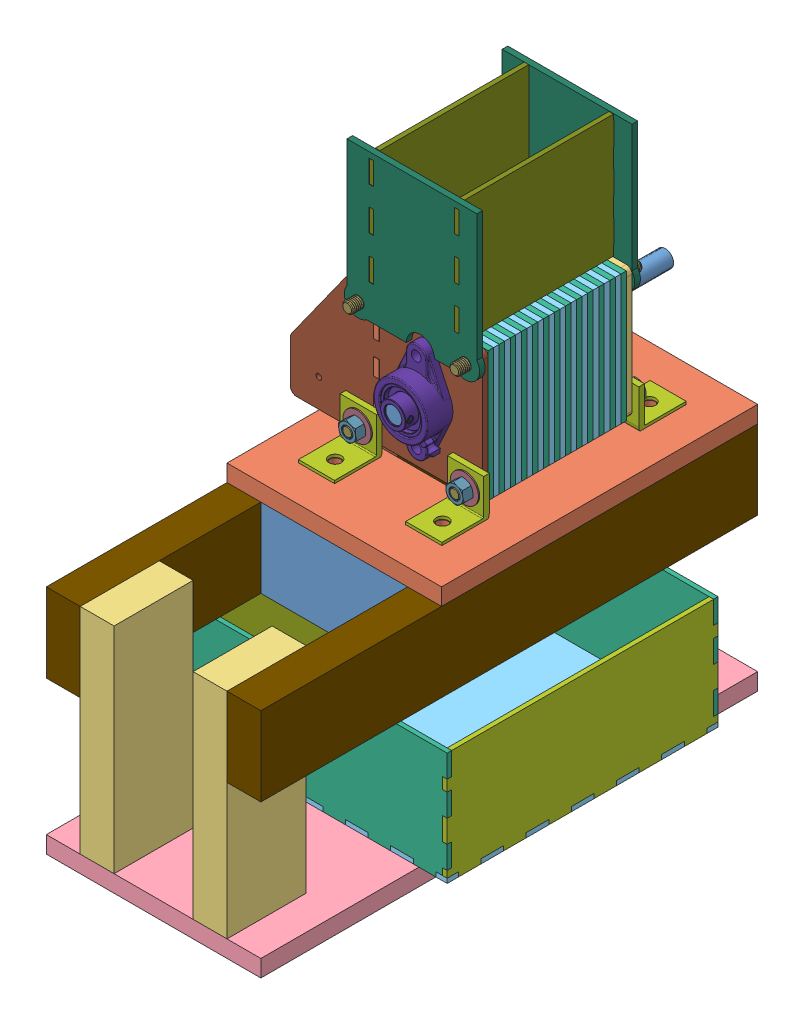
SolidWorks assembly Assembly_Single_Cutter_With_Gearbox, configuration Default. Lengths in mm.
Overall size (304.8 575.3 565.91).
95 component instances, 25 part files, 98 mates.
Components (placement in the parent):
- Axle-1: Axle [Default] at (0 0 48.387) x (0.906576 -0.422043 0) z (0 0 1) size (25.4 29.33 304.8)
- BackPlate-1: BackPlate [Default] at (-55.88 0 80.899) x (0 0 -1) z (1 0 0) size (168.66 146.05 6.35)
- Side_Plate-1: Side_Plate [Default] at origin size (146.05 146.05 6.35)
- Hex_Spacer-1: Hex_Spacer [Default] at (0 0 31.115) x (0.818788 0.574096 0) z (0 0 1) size (38.1 38.1 6.35)
- Hex_Spacer-2: Hex_Spacer [Default] at (0 0 18.669) x (0.818788 0.574096 0) z (0 0 1) size (38.1 38.1 6.35)
- Hex_Spacer-3: Hex_Spacer [Default] at (0 0 80.899) x (-0.818788 -0.574096 0) z (0 0 1) size (38.1 38.1 6.35)
- Hex_Spacer-13: Hex_Spacer [Default] at (0 0 6.223) x (0.818788 0.574096 0) z (0 0 1) size (38.1 38.1 6.35)
- Hex_Spacer-14: Hex_Spacer [Default] at (0 0 -0.127) x (0.818788 0.574096 0) z (0 0 1) size (38.1 38.1 6.35)
- Hex_Spacer-15: Hex_Spacer [Default] at (0 0 161.925) x (0.818788 0.574096 0) z (0 0 1) size (38.1 38.1 6.35)
- Spacer_1-1: Spacer_1 [Default] at (44.45 0 12.446) size (34.77 146.05 6.35)
- Spacer_2-1: Spacer_2 [Default] at (44.45 0 6.223) size (59.73 146.05 6.1)
- Spacer_2-14: Spacer_2 [Default] at (44.45 0 155.575) size (59.73 146.05 6.1)
- Spacer_2-2: Spacer_2 [Default] at (44.45 0 18.669) size (59.73 146.05 6.1)
- Spacer_2-3: Spacer_2 [Default] at (44.45 0 31.115) size (59.73 146.05 6.1)
- Spacer_2-4: Spacer_2 [Default] at (44.45 0 43.561) size (59.73 146.05 6.1)
- Spacer_2-5: Spacer_2 [Default] at (44.45 0 56.007) size (59.73 146.05 6.1)
- Spacer_2-6: Spacer_2 [Default] at (44.45 0 68.453) size (59.73 146.05 6.1)
- Spacer_2-7: Spacer_2 [Default] at (44.45 0 80.899) size (59.73 146.05 6.1)
- Spacer_2-8: Spacer_2 [Default] at (44.45 0 93.345) size (59.73 146.05 6.1)
- Spacer_2-9: Spacer_2 [Default] at (44.45 0 105.791) size (59.73 146.05 6.1)
- Spacer_2-10: Spacer_2 [Default] at (44.45 0 118.237) size (59.73 146.05 6.1)
- Spacer_2-11: Spacer_2 [Default] at (44.45 0 130.683) size (59.73 146.05 6.1)
- Spacer_2-12: Spacer_2 [Default] at (44.45 0 143.129) size (59.73 146.05 6.1)
- Spacer_1-3: Spacer_1 [Default] at (44.45 0 24.892) size (34.77 146.05 6.35)
- Spacer_1-4: Spacer_1 [Default] at (44.45 0 37.338) size (34.77 146.05 6.35)
- Spacer_1-5: Spacer_1 [Default] at (44.45 0 49.784) size (34.77 146.05 6.35)
- Spacer_1-6: Spacer_1 [Default] at (44.45 0 62.23) size (34.77 146.05 6.35)
- Spacer_1-7: Spacer_1 [Default] at (44.45 0 74.676) size (34.77 146.05 6.35)
- Spacer_1-8: Spacer_1 [Default] at (44.45 0 87.122) size (34.77 146.05 6.35)
- Spacer_1-9: Spacer_1 [Default] at (44.45 0 99.568) size (34.77 146.05 6.35)
- Spacer_1-10: Spacer_1 [Default] at (44.45 0 112.014) size (34.77 146.05 6.35)
- Spacer_1-11: Spacer_1 [Default] at (44.45 0 124.46) size (34.77 146.05 6.35)
- Spacer_1-12: Spacer_1 [Default] at (44.45 0 136.906) size (34.77 146.05 6.35)
- Spacer_1-13: Spacer_1 [Default] at (44.45 0 149.352) size (34.77 146.05 6.35)
- Base_Clamp-1: Base_Clamp [Default] at (-69.85 -80.01 171.323) x (0 1 0) z (1 0 0) size (46.99 53.34 40.64)
- Base_Clamp-2: Base_Clamp [Default] at (50.8 -80.01 171.323) x (0 1 0) z (1 0 0) size (46.99 53.34 40.64)
- Base_Clamp-3: Base_Clamp [Default] at (50.8 -80.01 -9.525) x (0 1 0) z (-1 0 0) size (46.99 53.34 40.64)
- Base_Clamp-4: Base_Clamp [Default] at (-69.85 -80.01 -9.525) x (0 1 0) z (-1 0 0) size (46.99 53.34 40.64)
- 2Tooth_Cutter_V1_2-1: 2Tooth_Cutter_V1_2 [Default] at (0 0 24.892) x (0.258206 0.96609 0) z (0 0 1) size (75.28 102.63 6.1)
- 2Tooth_Cutter_V1-1: 2Tooth_Cutter_V1 [Default] at (0 0 12.446) x (-0.087788 0.996139 0) z (0 0 1) size (75.28 104.14 6.1)
- 2Tooth_Cutter_V1_3-1: 2Tooth_Cutter_V1_3 [Default] at (0 0 37.338) x (0.573056 0.819516 0) z (0 0 1) size (75.28 102.63 6.1)
- Hex_Spacer-20: Hex_Spacer [Default] at (0 0 68.453) x (0.906576 -0.422043 0) z (0 0 1) size (38.1 38.1 6.35)
- Hex_Spacer-21: Hex_Spacer [Default] at (0 0 56.007) x (0.906576 -0.422043 0) z (0 0 1) size (38.1 38.1 6.35)
- Hex_Spacer-22: Hex_Spacer [Default] at (0 0 43.561) x (0.906576 -0.422043 0) z (0 0 1) size (38.1 38.1 6.35)
- 2Tooth_Cutter_V1_3-3: 2Tooth_Cutter_V1_3 [Default] at (0 0 74.676) x (0.99625 -0.086523 0) z (0 0 1) size (75.28 102.63 6.1)
- 2Tooth_Cutter_V1_2-3: 2Tooth_Cutter_V1_2 [Default] at (0 0 62.23) x (0.965761 0.259432 0) z (0 0 1) size (75.28 102.63 6.1)
- 2Tooth_Cutter_V1-3: 2Tooth_Cutter_V1 [Default] at (0 0 49.784) x (0.818788 0.574096 0) z (0 0 1) size (75.28 104.14 6.1)
- 2Tooth_Cutter_V1-4: 2Tooth_Cutter_V1 [Default] at (0 0 87.122) x (0.906576 -0.422043 0) z (0 0 1) size (75.28 104.14 6.1)
- 2Tooth_Cutter_V1-5: 2Tooth_Cutter_V1 [Default] at (0 0 124.46) x (0.087788 -0.996139 0) z (0 0 1) size (75.28 104.14 6.1)
- 2Tooth_Cutter_V1_2-4: 2Tooth_Cutter_V1_2 [Default] at (0 0 99.568) x (0.707556 -0.706658 0) z (0 0 1) size (75.28 102.63 6.1)
- 2Tooth_Cutter_V1_2-5: 2Tooth_Cutter_V1_2 [Default] at (0 0 136.906) x (-0.258206 -0.96609 0) z (0 0 1) size (75.28 102.63 6.1)
- 2Tooth_Cutter_V1_3-4: 2Tooth_Cutter_V1_3 [Default] at (0 0 112.014) x (0.423194 -0.906039 0) z (0 0 1) size (75.28 102.63 6.1)
- 2Tooth_Cutter_V1_3-5: 2Tooth_Cutter_V1_3 [Default] at (0 0 149.352) x (-0.573056 -0.819516 0) z (0 0 1) size (75.28 102.63 6.1)
- Hex_Spacer-23: Hex_Spacer [Default] at (0 0 80.899) x (0.087788 -0.996139 0) z (0 0 1) size (38.1 38.1 6.35)
- Hex_Spacer-24: Hex_Spacer [Default] at (0 0 118.237) x (-0.818788 -0.574096 0) z (0 0 1) size (38.1 38.1 6.35)
- Hex_Spacer-25: Hex_Spacer [Default] at (0 0 93.345) x (0.087788 -0.996139 0) z (0 0 1) size (38.1 38.1 6.35)
- Hex_Spacer-26: Hex_Spacer [Default] at (0 0 130.683) x (-0.818788 -0.574096 0) z (0 0 1) size (38.1 38.1 6.35)
- Hex_Spacer-27: Hex_Spacer [Default] at (0 0 105.791) x (0.087788 -0.996139 0) z (0 0 1) size (38.1 38.1 6.35)
- Hex_Spacer-28: Hex_Spacer [Default] at (0 0 143.129) x (-0.818788 -0.574096 0) z (0 0 1) size (38.1 38.1 6.35)
- Hex_Spacer-29: Hex_Spacer [Default] at (0 0 155.575) x (0.818788 0.574096 0) z (0 0 1) size (38.1 38.1 6.35)
- Side_Plate_With_Gear_Reduction-1: Side_Plate_With_Gear_Reduction [Default] at (0 0 161.798) size (215.9 146.05 6.35)
- 8in_Threaded_Rod-1: 8in_Threaded_Rod [3313N13] at (50.8 60.325 80.899) x (0 0 1) z (-1 0 0) size (209.49 12.88 14.68)
- 8in_Threaded_Rod-2: 8in_Threaded_Rod [3313N13] at (50.8 -60.325 80.899) x (0 0 1) z (-1 0 0) size (209.49 12.88 14.68)
- 8in_Threaded_Rod-3: 8in_Threaded_Rod [3313N13] at (-69.85 -60.325 80.899) x (0 0 1) z (-1 0 0) size (209.49 12.88 14.68)
- 8in_Threaded_Rod-4: 8in_Threaded_Rod [3313N13] at (-69.85 60.325 80.899) x (0 0 1) z (-1 0 0) size (209.49 12.88 14.68)
- 90107A033_TYPE 316 STAINLESS STEEL FLAT WASHER-2: 90107A033_TYPE 316 STAINLESS STEEL FLAT WASHER [90107A033] at (-69.85 -60.325 172.72) x (1 0 0) z (0 1 0) size (31.75 1.4 31.75)
- 90107A033_TYPE 316 STAINLESS STEEL FLAT WASHER-3: 90107A033_TYPE 316 STAINLESS STEEL FLAT WASHER [90107A033] at (50.8 -60.325 172.72) x (1 0 0) z (0 1 0) size (31.75 1.4 31.75)
- 95462A033_GRADE 5 STEEL HEX NUT-3: 95462A033_GRADE 5 STEEL HEX NUT [95462A033] at (-69.85 -60.325 178.2763) x (0.986139 0.165922 0) z (0 0 1) size (19.05 22 14.07)
- 95462A033_GRADE 5 STEEL HEX NUT-4: 95462A033_GRADE 5 STEEL HEX NUT [95462A033] at (50.8 -60.325 178.2763) x (0.983888 0.178788 0) z (0 0 1) size (19.05 22 14.07)
- 95462A033_GRADE 5 STEEL HEX NUT-5: 95462A033_GRADE 5 STEEL HEX NUT [95462A033] at (50.8 -60.325 -16.5447) x (0.983888 0.178788 0) z (0 0 1) size (19.05 22 14.07)
- 95462A033_GRADE 5 STEEL HEX NUT-6: 95462A033_GRADE 5 STEEL HEX NUT [95462A033] at (-69.85 -60.325 -16.5447) x (0.986139 0.165922 0) z (0 0 1) size (19.05 22 14.07)
- 90107A033_TYPE 316 STAINLESS STEEL FLAT WASHER-10: 90107A033_TYPE 316 STAINLESS STEEL FLAT WASHER [90107A033] at (50.8 -60.325 -10.922) x (1 0 0) z (0 -1 0) size (31.75 1.4 31.75)
- 90107A033_TYPE 316 STAINLESS STEEL FLAT WASHER-11: 90107A033_TYPE 316 STAINLESS STEEL FLAT WASHER [90107A033] at (-69.85 -60.325 -10.922) x (1 0 0) z (0 -1 0) size (31.75 1.4 31.75)
- Hopper_Front_Plate-1: Hopper_Front_Plate [Default] at (-9.525 60.325 -6.35) size (152.4 168.28 6.35)
- Hopper_Front_Plate-2: Hopper_Front_Plate [Default] at (-9.525 60.325 168.148) size (152.4 168.28 6.35)
- Hopper_Side_Plate-1: Hopper_Side_Plate [Default] at (-52.578 143.51 80.645) x (0 0 1) z (-1 0 0) size (180.34 138.43 5.08)
- Hopper_Side_Plate-2: Hopper_Side_Plate [Default] at (43.18 143.51 81.153) x (0 0 1) z (-1 0 0) size (180.34 138.43 5.08)
- 5968K730_TWO-BOLT FLANGE-MOUNT SELF-ALIGNING BALL BRNG-1: 5968K730_TWO-BOLT FLANGE-MOUNT SELF-ALIGNING BALL BRNG [5968K73] at (0 0 183.6261) x (0 -1 0) z (0 0 1) size (112.71 64.05 37.31)
- Shredder_Chassis_Subassembly-1: Shredder_Chassis_Subassembly [Default] at (-111.125 -146.6799 182.499) size (304.8 279.4 558.8)
  - Side_Wall-1: Side_Wall [Default] at origin size (38.1 88.9 558.8)
  - 2x4x6.5-1: 2x4x6.5 [Default] at (101.6 0 -260.35) x (0 0 1) z (-1 0 0) size (38.1 88.9 165.1)
  - Side_Wall-2: Side_Wall [Default] at (203.2 0 0) size (38.1 88.9 558.8)
  - 2x4x6.5-2: 2x4x6.5 [Default] at (101.6 0 57.15) x (0 0 1) z (-1 0 0) size (38.1 88.9 165.1)
  - Top_Plate-1: Top_Plate [Default] at (101.6 53.975 -101.6) size (241.3 19.05 355.6)
  - 2x4x9.5-1: 2x4x9.5 [Default] at (38.1 -76.2 234.95) size (38.1 241.3 88.9)
  - 2x4x9.5-2: 2x4x9.5 [Default] at (165.1 -76.2 234.95) size (38.1 241.3 88.9)
  - 2x4x9.5-3: 2x4x9.5 [Default] at (101.6 -76.2 -222.25) x (0 0 -1) z (1 0 0) size (38.1 241.3 88.9)
  - Bottom_Plate-1: Bottom_Plate [Default] at (101.6 -206.375 0) size (241.3 19.05 558.8)
  - Box_Subassembly-1: Box_Subassembly [Default] at (101.6 -194.31 -50.8) size (304.8 127 304.8)
    - Box_Bottom-1: Box_Bottom [Default] at origin size (304.8 5.08 304.8)
    - Box_Side1-1: Box_Side1 [Default] at (0 124.46 149.86) size (304.8 127 5.08)
    - Box_Side1-2: Box_Side1 [Default] at (0 124.46 -149.86) size (304.8 127 5.08)
    - Box_Side2-1: Box_Side2 [Default] at (149.86 124.46 0) x (0 0 -1) z (1 0 0) size (304.8 127 5.08)
    - Box_Side2-2: Box_Side2 [Default] at (-149.86 124.46 0) x (0 0 -1) z (1 0 0) size (304.8 127 5.08)
- 5968K730_TWO-BOLT FLANGE-MOUNT SELF-ALIGNING BALL BRNG-2: 5968K730_TWO-BOLT FLANGE-MOUNT SELF-ALIGNING BALL BRNG [5968K73] at (0 0 -21.8281) x (0 -1 0) z (0 0 -1) size (112.71 64.05 37.31)
Mates (geometry in assembly coordinates):
- Coincident15: coincident aligned: plane of BackPlate-1 through (-55.88 0 80.899) normal (0 1 0); plane of assembly through (0 0 0) normal (0 1 0)
- Coincident19: coincident aligned: plane of Side_Plate-1 through (0 0 0) normal (0 0 1); plane of assembly through (0 0 0) normal (0 0 1)
- Coincident20: coincident aligned: plane of Side_Plate-1 through (0 0 0) normal (1 0 0); plane of assembly through (0 0 0) normal (1 0 0)
- Coincident21: coincident aligned: plane of Side_Plate-1 through (0 0 0) normal (0 1 0); plane of assembly through (0 0 0) normal (0 1 0)
- Coincident22: coincident aligned: plane of BackPlate-1 through (-55.88 0 80.899) normal (1 0 0); plane of assembly through (-55.88 0 0) normal (1 0 0)
- Coincident23: coincident anti-aligned: plane of BackPlate-1 through (-52.705 73.025 3.175) normal (0 0 -1); plane of Side_Plate-1 through (0 0 3.175) normal (0 0 1)
- Concentric9: concentric aligned: cylinder of Axle-1 through (0 0 200.787) axis (0 0 -1) radius 9.525; cylinder of Side_Plate-1 through (0 0 3.175) axis (0 0 -1) radius 19.05
- Coincident25: coincident aligned: line of Axle-1 through (-14.6081 -1.2874 165.227) axis (0 0 -1); line of Hex_Spacer-1 through (-14.6081 -1.2874 34.29) axis (0 0 -1)
- Coincident26: coincident aligned: line of Axle-1 through (14.6081 1.2874 165.227) axis (0 0 -1); line of Hex_Spacer-1 through (14.6081 1.2874 34.29) axis (0 0 -1)
- Concentric14: concentric aligned: cylinder of Side_Plate-1 through (50.8 -60.325 3.175) axis (0 0 -1) radius 6.35; cylinder of Spacer_1-1 through (50.8 -60.325 15.621) axis (0 0 -1) radius 6.3627
- Concentric15: concentric aligned: cylinder of Side_Plate-1 through (50.8 60.325 3.175) axis (0 0 -1) radius 6.35; cylinder of Spacer_1-1 through (50.8 60.325 15.621) axis (0 0 -1) radius 6.3627
- Concentric16: concentric aligned: cylinder of Side_Plate-1 through (50.8 60.325 3.175) axis (0 0 -1) radius 6.35; cylinder of Spacer_2-1 through (50.8 60.325 9.271) axis (0 0 -1) radius 6.3627
- Concentric17: concentric aligned: cylinder of Side_Plate-1 through (50.8 -60.325 3.175) axis (0 0 -1) radius 6.35; cylinder of Spacer_2-1 through (50.8 -60.325 9.271) axis (0 0 -1) radius 6.3627
- Coincident38: coincident anti-aligned: plane of Side_Plate-1 through (0 0 3.175) normal (0 0 1); plane of Spacer_2-1 through (44.45 0 3.175) normal (0 0 -1)
- Coincident39: coincident anti-aligned: plane of Spacer_1-1 through (44.45 0 9.271) normal (0 0 -1); plane of Spacer_2-1 through (44.45 0 9.271) normal (0 0 1)
- Coincident40: coincident anti-aligned: plane of Spacer_1-13 through (44.45 0 152.527) normal (0 0 1); plane of Spacer_2-14 through (44.45 0 152.527) normal (0 0 -1)
- Concentric19: concentric aligned: cylinder of Side_Plate-1 through (50.8 -60.325 3.175) axis (0 0 -1) radius 6.35; cylinder of Spacer_2-14 through (50.8 -60.325 158.623) axis (0 0 -1) radius 6.3627
- Concentric20: concentric aligned: cylinder of Side_Plate-1 through (50.8 60.325 3.175) axis (0 0 -1) radius 6.35; cylinder of Spacer_2-14 through (50.8 60.325 158.623) axis (0 0 -1) radius 6.3627
- Coincident44: coincident aligned: line of Axle-1 through (6.1891 13.2947 165.227) axis (0 0 -1); line of Hex_Spacer-2 through (6.1891 13.2947 21.844) axis (0 0 -1)
- Coincident45: coincident aligned: line of Axle-1 through (-6.1891 -13.2947 165.227) axis (0 0 -1); line of Hex_Spacer-2 through (-6.1891 -13.2947 21.844) axis (0 0 -1)
- Coincident54: coincident aligned: line of Axle-1 through (8.419 -12.0073 165.227) axis (0 0 -1); line of Hex_Spacer-3 through (8.419 -12.0073 84.074) axis (0 0 -1)
- Coincident55: coincident aligned: line of Axle-1 through (6.1891 13.2947 165.227) axis (0 0 -1); line of Hex_Spacer-3 through (6.1891 13.2947 84.074) axis (0 0 -1)
- Coincident57: coincident aligned: plane of Axle-1 through (0 0 -3.175) normal (0 0 -1); plane of Side_Plate-1 through (0 0 -3.175) normal (0 0 -1)
- Coincident58: coincident aligned: line of Axle-1 through (6.1891 13.2947 165.227) axis (0 0 -1); line of Hex_Spacer-13 through (6.1891 13.2947 9.398) axis (0 0 -1)
- Coincident59: coincident aligned: line of Axle-1 through (-6.1891 -13.2947 165.227) axis (0 0 -1); line of Hex_Spacer-13 through (-6.1891 -13.2947 9.398) axis (0 0 -1)
- Coincident61: coincident aligned: line of Axle-1 through (6.1891 13.2947 165.227) axis (0 0 -1); line of Hex_Spacer-14 through (6.1891 13.2947 3.048) axis (0 0 -1)
- Coincident62: coincident aligned: line of Axle-1 through (-6.1891 -13.2947 165.227) axis (0 0 -1); line of Hex_Spacer-14 through (-6.1891 -13.2947 3.048) axis (0 0 -1)
- Coincident63: coincident anti-aligned: plane of Hex_Spacer-13 through (0 0 3.048) normal (0 0 -1); plane of Hex_Spacer-14 through (0 0 3.048) normal (0 0 1)
- Coincident64: coincident aligned: line of Axle-1 through (6.1891 13.2947 165.227) axis (0 0 -1); line of Hex_Spacer-15 through (6.1891 13.2947 165.1) axis (0 0 -1)
- Coincident65: coincident aligned: line of Axle-1 through (-6.1891 -13.2947 165.227) axis (0 0 -1); line of Hex_Spacer-15 through (-6.1891 -13.2947 165.1) axis (0 0 -1)
- Coincident69: coincident aligned: plane of Spacer_1-1 through (44.45 0 12.446) normal (0 0 1); plane of 2Tooth_Cutter_V1-1 through (0 0 12.446) normal (0 0 1)
- Parallel1: parallel aligned: line of Axle-1 through (8.419 -12.0073 165.227) axis (0 0 -1); line of 2Tooth_Cutter_V1_2-1 through (-8.419 12.0073 27.94) axis (0 0 -1)
- Coincident80: coincident aligned: line of Axle-1 through (-8.419 12.0073 165.227) axis (0 0 -1); line of 2Tooth_Cutter_V1-1 through (-8.419 12.0073 15.494) axis (0 0 -1)
- Coincident81: coincident aligned: line of Axle-1 through (-6.1891 -13.2947 165.227) axis (0 0 -1); line of 2Tooth_Cutter_V1-1 through (-6.1891 -13.2947 15.494) axis (0 0 -1)
- Coincident82: coincident aligned: line of Axle-1 through (-8.419 12.0073 165.227) axis (0 0 -1); line of 2Tooth_Cutter_V1_2-1 through (-8.419 12.0073 27.94) axis (0 0 -1)
- Coincident83: coincident aligned: line of Axle-1 through (-6.1891 -13.2947 165.227) axis (0 0 -1); line of 2Tooth_Cutter_V1_2-1 through (-6.1891 -13.2947 27.94) axis (0 0 -1)
- Coincident84: coincident anti-aligned: plane of Hex_Spacer-2 through (0 0 21.844) normal (0 0 1); plane of 2Tooth_Cutter_V1_2-1 through (0 0 21.844) normal (0 0 -1)
- Coincident85: coincident anti-aligned: plane of Hex_Spacer-2 through (0 0 15.494) normal (0 0 -1); plane of 2Tooth_Cutter_V1-1 through (0 0 15.494) normal (0 0 1)
- Coincident87: coincident aligned: line of Axle-1 through (-8.419 12.0073 165.227) axis (0 0 -1); line of 2Tooth_Cutter_V1_3-1 through (-8.419 12.0073 40.386) axis (0 0 -1)
- Coincident88: coincident aligned: line of Axle-1 through (-6.1891 -13.2947 165.227) axis (0 0 -1); line of 2Tooth_Cutter_V1_3-1 through (-6.1891 -13.2947 40.386) axis (0 0 -1)
- Coincident89: coincident anti-aligned: plane of Hex_Spacer-1 through (0 0 27.94) normal (0 0 -1); plane of 2Tooth_Cutter_V1_2-1 through (0 0 27.94) normal (0 0 1)
- Coincident90: coincident anti-aligned: plane of Hex_Spacer-1 through (0 0 34.29) normal (0 0 1); plane of 2Tooth_Cutter_V1_3-1 through (0 0 34.29) normal (0 0 -1)
- Coincident91: coincident anti-aligned: plane of Hex_Spacer-3 through (0 0 77.724) normal (0 0 -1); plane of 2Tooth_Cutter_V1_3-3 through (0 0 77.724) normal (0 0 1)
- Coincident92: coincident aligned: line of Axle-1 through (8.419 -12.0073 165.227) axis (0 0 -1); line of Hex_Spacer-29 through (8.419 -12.0073 158.75) axis (0 0 -1)
- Coincident93: coincident aligned: line of Axle-1 through (14.6081 1.2874 165.227) axis (0 0 -1); line of Hex_Spacer-29 through (14.6081 1.2874 158.75) axis (0 0 -1)
- Coincident94: coincident anti-aligned: plane of 2Tooth_Cutter_V1_3-5 through (0 0 152.4) normal (0 0 1); plane of Hex_Spacer-29 through (0 0 152.4) normal (0 0 -1)
- Coincident95: coincident anti-aligned: plane of Hex_Spacer-15 through (0 0 158.75) normal (0 0 -1); plane of Hex_Spacer-29 through (0 0 158.75) normal (0 0 1)
- Concentric21: concentric aligned: cylinder of Spacer_2-14 through (50.8 -60.325 158.623) axis (0 0 -1) radius 6.3627; cylinder of Side_Plate_With_Gear_Reduction-1 through (50.8 -60.325 164.973) axis (0 0 -1) radius 6.35
- Coincident96: coincident anti-aligned: plane of Spacer_2-14 through (44.45 0 158.623) normal (0 0 1); plane of Side_Plate_With_Gear_Reduction-1 through (0 0 158.623) normal (0 0 -1)
- Concentric22: concentric aligned: cylinder of Spacer_2-14 through (50.8 60.325 158.623) axis (0 0 -1) radius 6.3627; cylinder of Side_Plate_With_Gear_Reduction-1 through (50.8 60.325 164.973) axis (0 0 -1) radius 6.35
- Concentric23: concentric anti-aligned: cylinder of Side_Plate_With_Gear_Reduction-1 through (-69.85 -60.325 164.973) axis (0 0 -1) radius 6.35; cylinder of Base_Clamp-1 through (-69.85 -60.325 164.972) axis (0 0 1) radius 6.985
- Coincident97: coincident anti-aligned: plane of Side_Plate_With_Gear_Reduction-1 through (0 0 164.973) normal (0 0 1); plane of Base_Clamp-1 through (-49.53 -78.74 164.973) normal (0 0 -1)
- Parallel2: parallel aligned: plane of BackPlate-1 through (-52.705 -73.025 3.175) normal (0 -1 0); plane of Base_Clamp-1 through (-49.53 -86.36 218.313) normal (0 -1 0)
- Concentric24: concentric anti-aligned: cylinder of Side_Plate_With_Gear_Reduction-1 through (50.8 -60.325 164.973) axis (0 0 -1) radius 6.35; cylinder of Base_Clamp-2 through (50.8 -60.325 164.972) axis (0 0 1) radius 6.985
- Coincident99: coincident anti-aligned: plane of Side_Plate_With_Gear_Reduction-1 through (0 0 164.973) normal (0 0 1); plane of Base_Clamp-2 through (71.12 -78.74 164.973) normal (0 0 -1)
- Coincident100: coincident aligned: plane of Base_Clamp-1 through (-49.53 -86.36 218.313) normal (0 -1 0); plane of Base_Clamp-2 through (71.12 -86.36 218.313) normal (0 -1 0)
- Coincident101: coincident anti-aligned: plane of Side_Plate-1 through (0 0 -3.175) normal (0 0 -1); plane of Base_Clamp-3 through (30.48 -78.74 -3.175) normal (0 0 1)
- Concentric25: concentric aligned: cylinder of Side_Plate-1 through (50.8 -60.325 3.175) axis (0 0 -1) radius 6.35; cylinder of Base_Clamp-3 through (50.8 -60.325 -3.174) axis (0 0 -1) radius 6.985
- Coincident102: coincident aligned: plane of Base_Clamp-2 through (71.12 -86.36 218.313) normal (0 -1 0); plane of Base_Clamp-3 through (30.48 -86.36 -56.515) normal (0 -1 0)
- Coincident103: coincident anti-aligned: plane of Side_Plate-1 through (0 0 -3.175) normal (0 0 -1); plane of Base_Clamp-4 through (-90.17 -78.74 -3.175) normal (0 0 1)
- Concentric26: concentric aligned: cylinder of Side_Plate-1 through (-69.85 -60.325 3.175) axis (0 0 -1) radius 6.35; cylinder of Base_Clamp-4 through (-69.85 -60.325 -3.174) axis (0 0 -1) radius 6.985
- Coincident104: coincident aligned: plane of Base_Clamp-3 through (30.48 -86.36 -56.515) normal (0 -1 0); plane of Base_Clamp-4 through (-90.17 -86.36 -56.515) normal (0 -1 0)
- Concentric27: concentric anti-aligned: cylinder of Side_Plate_With_Gear_Reduction-1 through (50.8 60.325 164.973) axis (0 0 -1) radius 6.35; line of 8in_Threaded_Rod-1 through (50.8 60.325 -20.6326) axis (0 0 1)
- Coincident105: coincident aligned: plane of 8in_Threaded_Rod-1 through (50.8 60.325 80.899) normal (0 0 1); plane of assembly through (0 0 80.899) normal (0 0 1)
- Concentric28: concentric aligned: cylinder of Base_Clamp-1 through (-69.85 -60.325 164.972) axis (0 0 1) radius 6.985; line of 8in_Threaded_Rod-3 through (-69.85 -60.325 -20.6326) axis (0 0 1)
- Coincident106: coincident aligned: plane of 8in_Threaded_Rod-3 through (-69.85 -60.325 80.899) normal (0 0 1); plane of assembly through (0 0 80.899) normal (0 0 1)
- Concentric30: concentric aligned: cylinder of Base_Clamp-2 through (50.8 -60.325 164.972) axis (0 0 1) radius 6.985; line of 8in_Threaded_Rod-2 through (50.8 -60.325 -20.6326) axis (0 0 1)
- Coincident107: coincident aligned: plane of 8in_Threaded_Rod-2 through (50.8 -60.325 80.899) normal (0 0 1); plane of assembly through (0 0 80.899) normal (0 0 1)
- Concentric31: concentric anti-aligned: cylinder of Side_Plate_With_Gear_Reduction-1 through (-69.85 60.325 164.973) axis (0 0 -1) radius 6.35; line of 8in_Threaded_Rod-4 through (-69.85 60.325 -20.6326) axis (0 0 1)
- Coincident108: coincident aligned: plane of 8in_Threaded_Rod-4 through (-69.85 60.325 80.899) normal (0 0 1); plane of assembly through (0 0 80.899) normal (0 0 1)
- Coincident110: coincident anti-aligned: plane of Base_Clamp-1 through (-49.53 -39.37 171.323) normal (0 0 1); plane of 90107A033_TYPE 316 STAINLESS STEEL FLAT WASHER-2 through (-69.85 -60.325 171.323) normal (0 0 -1)
- Concentric33: concentric anti-aligned: line of 8in_Threaded_Rod-3 through (-69.85 -60.325 -20.6326) axis (0 0 1); cylinder of 90107A033_TYPE 316 STAINLESS STEEL FLAT WASHER-2 through (-69.85 -60.325 172.72) axis (0 0 -1) radius 6.7437
- Concentric34: concentric anti-aligned: line of 8in_Threaded_Rod-2 through (50.8 -60.325 -20.6326) axis (0 0 1); cylinder of 90107A033_TYPE 316 STAINLESS STEEL FLAT WASHER-3 through (50.8 -60.325 172.72) axis (0 0 -1) radius 6.7437
- Coincident111: coincident anti-aligned: plane of Base_Clamp-2 through (71.12 -39.37 171.323) normal (0 0 1); plane of 90107A033_TYPE 316 STAINLESS STEEL FLAT WASHER-3 through (50.8 -60.325 171.323) normal (0 0 -1)
- Coincident117: coincident anti-aligned: line of 8in_Threaded_Rod-3 through (-69.85 -60.325 -20.6326) axis (0 0 1); line of 95462A033_GRADE 5 STEEL HEX NUT-3 through (-69.85 -60.325 183.8325) axis (0 0 -1)
- Coincident118: coincident anti-aligned: plane of 90107A033_TYPE 316 STAINLESS STEEL FLAT WASHER-2 through (-69.85 -60.325 172.72) normal (0 0 1); plane of 95462A033_GRADE 5 STEEL HEX NUT-3 through (-80.1554 -56.4824 172.72) normal (0 0 -1)
- Coincident119: coincident anti-aligned: line of 8in_Threaded_Rod-2 through (50.8 -60.325 -20.6326) axis (0 0 1); line of 95462A033_GRADE 5 STEEL HEX NUT-4 through (50.8 -60.325 186.9915) axis (0 0 -1)
- Coincident120: coincident anti-aligned: plane of 90107A033_TYPE 316 STAINLESS STEEL FLAT WASHER-3 through (50.8 -60.325 172.72) normal (0 0 1); plane of 95462A033_GRADE 5 STEEL HEX NUT-4 through (40.4453 -56.6173 172.72) normal (0 0 -1)
- Coincident124: coincident anti-aligned: plane of Side_Plate-1 through (0 0 -3.175) normal (0 0 -1); plane of Hopper_Front_Plate-1 through (-9.525 60.325 -3.175) normal (0 0 1)
- Concentric39: concentric anti-aligned: cylinder of 8in_Threaded_Rod-4 through (-69.85 60.325 -22.098) axis (0 0 1) radius 6.35; cylinder of Hopper_Front_Plate-1 through (-69.85 60.325 -3.175) axis (0 0 -1) radius 6.35
- Concentric40: concentric anti-aligned: cylinder of 8in_Threaded_Rod-1 through (50.8 60.325 -22.098) axis (0 0 1) radius 6.35; cylinder of Hopper_Front_Plate-1 through (50.8 60.325 -3.175) axis (0 0 -1) radius 6.35
- Concentric41: concentric anti-aligned: cylinder of 8in_Threaded_Rod-4 through (-69.85 60.325 -22.098) axis (0 0 1) radius 6.35; cylinder of Hopper_Front_Plate-2 through (-69.85 60.325 171.323) axis (0 0 -1) radius 6.35
- Coincident125: coincident anti-aligned: plane of Side_Plate_With_Gear_Reduction-1 through (0 0 164.973) normal (0 0 1); plane of Hopper_Front_Plate-2 through (-9.525 60.325 164.973) normal (0 0 -1)
- Concentric42: concentric anti-aligned: cylinder of 8in_Threaded_Rod-1 through (50.8 60.325 -22.098) axis (0 0 1) radius 6.35; cylinder of Hopper_Front_Plate-2 through (50.8 60.325 171.323) axis (0 0 -1) radius 6.35
- Coincident126: coincident anti-aligned: plane of Hopper_Front_Plate-1 through (-9.525 60.325 -3.175) normal (0 0 1); plane of Hopper_Side_Plate-1 through (-57.658 158.75 -3.175) normal (0 0 -1)
- Coincident127: coincident anti-aligned: plane of Hopper_Front_Plate-1 through (-57.658 180.975 -9.525) normal (0 1 0); plane of Hopper_Side_Plate-1 through (-57.658 180.975 -3.175) normal (0 -1 0)
- Coincident128: coincident anti-aligned: plane of Hopper_Front_Plate-1 through (-57.658 206.375 -9.525) normal (1 0 0); plane of Hopper_Side_Plate-1 through (-57.658 143.51 80.645) normal (-1 0 0)
- Coincident129: coincident anti-aligned: plane of Hopper_Front_Plate-2 through (38.1 206.375 164.973) normal (1 0 0); plane of Hopper_Side_Plate-2 through (38.1 143.51 81.153) normal (-1 0 0)
- Coincident130: coincident anti-aligned: plane of Hopper_Front_Plate-2 through (-9.525 60.325 164.973) normal (0 0 -1); plane of Hopper_Side_Plate-2 through (38.1 206.375 164.973) normal (0 0 1)
- Coincident131: coincident anti-aligned: plane of Hopper_Front_Plate-2 through (38.1 180.975 164.973) normal (0 1 0); plane of Hopper_Side_Plate-2 through (38.1 180.975 164.973) normal (0 -1 0)
- Coincident132: coincident anti-aligned: plane of Side_Plate_With_Gear_Reduction-1 through (0 0 164.973) normal (0 0 1); plane of 5968K730_TWO-BOLT FLANGE-MOUNT SELF-ALIGNING BALL BRNG-1 through (0 0 164.973) normal (0 0 -1)
- Concentric50: concentric aligned: cylinder of Axle-1 through (0 0 200.787) axis (0 0 -1) radius 9.525; cylinder of 5968K730_TWO-BOLT FLANGE-MOUNT SELF-ALIGNING BALL BRNG-1 through (0 0 202.2792) axis (0 0 -1) radius 9.525
- Coincident133: coincident aligned: plane of 5968K730_TWO-BOLT FLANGE-MOUNT SELF-ALIGNING BALL BRNG-1 through (0 0 183.6261) normal (1 0 0)
- Concentric51: concentric aligned: cylinder of Base_Clamp-3 through (50.8 -86.361 -35.56) axis (0 1 0) radius 6.985; cylinder of Shredder_Chassis_Subassembly-1/Top_Plate-1 through (50.8 -102.2299 -35.56) axis (0 1 0) radius 6.35
- Concentric52: concentric aligned: cylinder of Base_Clamp-1 through (-69.85 -86.361 197.358) axis (0 1 0) radius 6.985; cylinder of Shredder_Chassis_Subassembly-1/Top_Plate-1 through (-69.85 -102.2299 197.358) axis (0 1 0) radius 6.35
- Concentric53: concentric anti-aligned: cylinder of Axle-1 through (0 0 200.787) axis (0 0 -1) radius 9.525; cylinder of 5968K730_TWO-BOLT FLANGE-MOUNT SELF-ALIGNING BALL BRNG-2 through (0 0 -40.4813) axis (0 0 1) radius 9.525
- Coincident134: coincident anti-aligned: plane of Side_Plate-1 through (0 0 -3.175) normal (0 0 -1); plane of 5968K730_TWO-BOLT FLANGE-MOUNT SELF-ALIGNING BALL BRNG-2 through (0 0 -3.175) normal (0 0 1)
- Coincident135: coincident anti-aligned: plane of 5968K730_TWO-BOLT FLANGE-MOUNT SELF-ALIGNING BALL BRNG-2 through (0 0 -21.8281) normal (-1 0 0)
